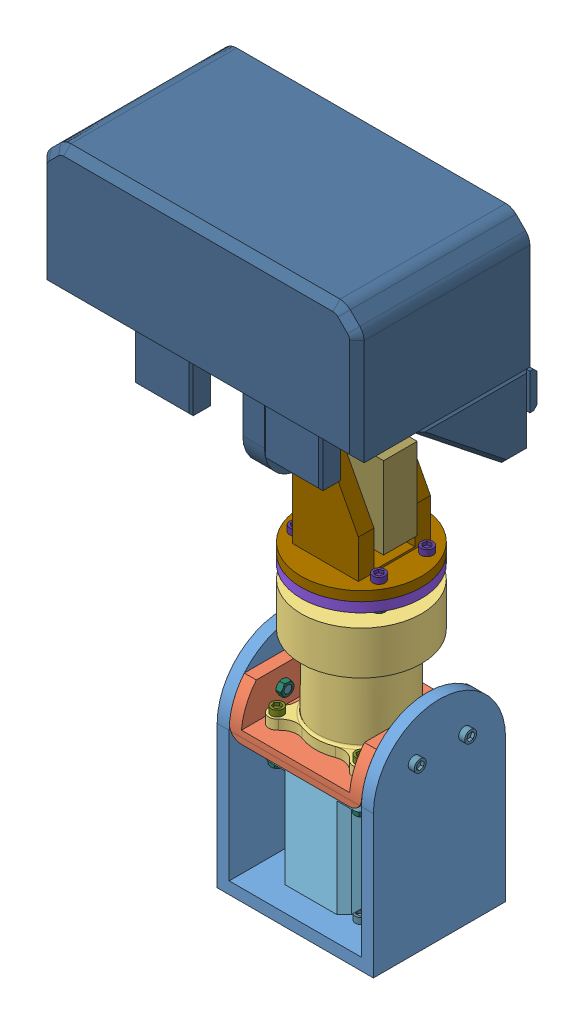
SolidWorks assembly camera, configuration Default. Lengths in mm.
Overall size (132 263.13 83.4).
66 component instances, 20 part files, 134 mates.
Components (placement in the parent):
- Part1-1: Part1 [Default] at origin size (65 86.75 55)
- Part2-1: Part2 [Default] at (0 56.75 0) x (0 0 1) z (-1 0 0) size (55 20 55)
- Part3-2: Part3 [Default] at (0 61.75 0) size (50 52 50)
- Stepper motor-1: Stepper motor [Default] at (0 56.75 0) x (0 0 1) z (-1 0 0) size (42 61 42) (flexible)
  - shaft for stpmotor-1: shaft for stpmotor [Default] at (0 -15 0) x (0.964656 0 0.263513) z (-0.263513 0 0.964656) size (5.6 28 5.6)
  - stepper motor-1-1: stepper motor-1 [Default] x (-1 0 0) z (0 0 1) size (42 48 42)
  - stepper motor-2-1: stepper motor-2 [Default] at (0 -15 0) x (0.798923 0 -0.601433) z (0.601433 0 0.798923) size (28 16.05 28)
- thrust needle bearing_is-2: thrust needle bearing_is [IS 4215 TN - AXZ614-D] at (0 102.5 0) x (0.948007 0 0.31825) z (0 -1 0) size (14 14 5.5)
- Part4-1: Part4 [Default] at (0 105.25 0) x (-1 0 0) z (0 0 -1) size (50 18 50)
- Part5-1: Part5 [Default] at (0 123.25 0) x (-1 0 0) z (0 0 -1) size (50 54 50)
- Head-1: Head [Default] at (-18.5476 153.5942 18.0553) x (-1 0 0) z (0 0 -1) size (132 111 83.4)
- Part6-1: Part6 [Default] at (-27.75 161.0422 0) x (0 -1 0) z (0 0 1) size (25 11 25)
- Servo motor-1: Servo motor [Default] at (-13.75 151.0422 0) x (0 0 1) z (0 1 0) size (14 30 44)
- servo shaft-1: servo shaft [Default] at (-19.75 161.0422 0) x (0 0.765773 -0.643111) z (0 -0.643111 -0.765773) size (5 18 5)
- M3 bolt for camera-1-1: M3 bolt for camera-1 [Default] at (-33.75 69.25 -10.5) x (0 -0.989932 0.141542) z (1 0 0) size (5 5 15.19)
- M3 bolt for camera-1-2: M3 bolt for camera-1 [Default] at (-33.75 69.25 10.5) x (0 0.287903 -0.95766) z (1 0 0) size (5 5 15.19)
- M3 bolt for camera-1-3: M3 bolt for camera-1 [Default] at (33.75 69.25 -10.5) x (0 -0.601923 0.798554) z (-1 0 0) size (5 5 15.19)
- M3 bolt for camera-1-4: M3 bolt for camera-1 [Default] at (33.75 69.25 10.5) x (0 -0.806228 0.591605) z (-1 0 0) size (5 5 15.19)
- M3 nut-1: M3 nut [Default] at (21.25 69.25 -10.5) x (0 0 -1) z (1 0 0) size (5 6.35 2.75)
- M3 nut-2: M3 nut [Default] at (21.25 69.25 10.5) x (0 0.10842 -0.994105) z (1 0 0) size (5 6.35 2.75)
- M3 nut-3: M3 nut [Default] at (-21.25 69.25 -10.5) x (0 -0.15906 -0.987269) z (1 0 0) size (5 6.35 2.75)
- M3 nut-5: M3 nut [Default] at (-21.25 69.25 10.5) x (0 -0.536596 -0.843839) z (1 0 0) size (5 6.35 2.75)
- M3 bolt for camera-1-5: M3 bolt for camera-1 [Default] at (14 6.25 -14) x (0.844498 0 0.535559) z (0 -1 0) size (5 5 15.19)
- M3 bolt for camera-1-6: M3 bolt for camera-1 [Default] at (-14 6.25 -14) x (0.844498 0 0.535559) z (0 -1 0) size (5 5 15.19)
- M3 bolt for camera-1-7: M3 bolt for camera-1 [Default] at (-14 6.25 14) x (0.844498 0 0.535559) z (0 -1 0) size (5 5 15.19)
- M3 bolt for camera-1-8: M3 bolt for camera-1 [Default] at (14 6.25 14) x (0.875078 0 0.483982) z (0 -1 0) size (5 5 15.19)
- M3 bolt for camera-2-1: M3 bolt for camera-2 [Default] at (-17.5 67 -17.5) x (0.961906 0 -0.273382) z (0 -1 0) size (5 5 21.24)
- M3 bolt for camera-2-2: M3 bolt for camera-2 [Default] at (17.5 67 -17.5) x (0.940508 0 -0.339772) z (0 -1 0) size (5 5 21.24)
- M3 bolt for camera-2-3: M3 bolt for camera-2 [Default] at (-17.5 67 17.5) x (0.940508 0 -0.339772) z (0 -1 0) size (5 5 21.24)
- M3 bolt for camera-2-4: M3 bolt for camera-2 [Default] at (17.5 67 17.5) x (0.531388 0 -0.847129) z (0 -1 0) size (5 5 21.24)
- M3 nut-6: M3 nut [Default] at (17.5 48.5 -17.5) x (0 0 -1) z (0 1 0) size (5 6.35 2.75)
- M3 nut-7: M3 nut [Default] at (17.5 48.5 17.5) x (0 0 -1) z (0 1 0) size (5 6.35 2.75)
- M3 nut-8: M3 nut [Default] at (-17.5 48.5 17.5) x (0 0 -1) z (0 -1 0) size (5 6.35 2.75)
- M3 nut-9: M3 nut [Default] at (-17.5 48.5 -17.5) x (0 0 -1) z (0 -1 0) size (5 6.35 2.75)
- M3 nut-10: M3 nut [Default] at (-14 -6.3102 14) x (-0.119007 0 -0.992893) z (0 1 0) size (5 6.35 2.75)
- M3 nut-11: M3 nut [Default] at (14 -6.2794 14) x (-0.305046 0 -0.952338) z (0 1 0) size (5 6.35 2.75)
- M3 nut-12: M3 nut [Default] at (-14 -6.1955 -14) x (-0.334167 0 -0.942514) z (0 1 0) size (5 6.35 2.75)
- M3 nut-13: M3 nut [Default] at (14 -6.5015 -14) x (0.157974 0 -0.987443) z (0 1 0) size (5 6.35 2.75)
- M3 bolt for camera-3-1: M3 bolt for camera-3 [Default] at (17.3205 128.5 10) x (0.981592 0 0.190988) z (0 -1 0) size (5 5 13.17)
- M3 bolt for camera-3-2: M3 bolt for camera-3 [Default] at (-17.3205 128.5 10) x (1 0 0) z (0 -1 0) size (5 5 13.17)
- M3 bolt for camera-3-3: M3 bolt for camera-3 [Default] at (-17.3205 128.5 -10) x (1 0 0) z (0 -1 0) size (5 5 13.17)
- M3 bolt for camera-3-4: M3 bolt for camera-3 [Default] at (17.3205 128.5 -10) x (0.282478 0 0.959274) z (0 -1 0) size (5 5 13.17)
- M3 nut-14: M3 nut [Default] at (17.3205 118 -10) x (-0.536596 0 -0.843839) z (0 -1 0) size (5 6.35 2.75)
- M3 nut-15: M3 nut [Default] at (17.3205 118 10) x (-0.536596 0 -0.843839) z (0 -1 0) size (5 6.35 2.75)
- M3 nut-16: M3 nut [Default] at (-17.3205 118 10) x (0.536596 0 -0.843839) z (0 1 0) size (5 6.35 2.75)
- M3 nut-17: M3 nut [Default] at (-17.3205 118 -10) x (0.536596 0 -0.843839) z (0 1 0) size (5 6.35 2.75)
- M3 bolt for camera-3-5: M3 bolt for camera-3 [Default] at (-8 131.0322 -4.55) x (0 0.374777 0.927115) z (-1 0 0) size (5 5 13.17)
- M3 bolt for camera-3-6: M3 bolt for camera-3 [Default] at (-8 131.0322 4.55) x (0 0.504845 0.86321) z (-1 0 0) size (5 5 13.17)
- M3 bolt for camera-3-7: M3 bolt for camera-3 [Default] at (-8 171.0522 4.55) x (0 0.374777 0.927115) z (-1 0 0) size (5 5 13.17)
- M3 bolt for camera-3-8: M3 bolt for camera-3 [Default] at (-8 171.0522 -4.55) x (0 0.374777 0.927115) z (-1 0 0) size (5 5 13.17)
- M3 nut-18: M3 nut [Default] at (-15 131.0322 4.55) x (0 -0.733053 -0.680172) z (1 0 0) size (5 6.35 2.75)
- M3 nut-19: M3 nut [Default] at (-15 131.0322 -4.55) x (0 -0.733053 -0.680172) z (1 0 0) size (5 6.35 2.75)
- M3 nut-20: M3 nut [Default] at (-15 171.0522 4.55) x (0 -0.733053 -0.680172) z (1 0 0) size (5 6.35 2.75)
- M3 nut-21: M3 nut [Default] at (-15 171.0522 -4.55) x (0 0.733053 -0.680172) z (-1 0 0) size (5 6.35 2.75)
- M3 bolt for camera-3-9: M3 bolt for camera-3 [Default] at (-32 155.0318 -6.0104) x (0 -0.010427 0.999946) z (1 0 0) size (5 5 13.17)
- M3 bolt for camera-3-11: M3 bolt for camera-3 [Default] at (-32 167.0526 6.0104) x (0 -0.369002 0.929429) z (1 0 0) size (5 5 13.17)
- M3 bolt for camera-3-12: M3 bolt for camera-3 [Default] at (-32 155.0318 6.0104) x (0 -0.369002 0.929429) z (1 0 0) size (5 5 13.17)
- M3 bolt for camera-3-13: M3 bolt for camera-3 [Default] at (-32 167.0526 -6.0104) x (0 -0.369002 0.929429) z (1 0 0) size (5 5 13.17)
- M3 nut-22: M3 nut [Default] at (-22.5 155.0318 -6.0104) x (0 0.733053 -0.680172) z (-1 0 0) size (5 6.35 2.75)
- M3 nut-23: M3 nut [Default] at (-22.5 155.0318 6.0104) x (0 -0.239551 -0.970884) z (-1 0 0) size (5 6.35 2.75)
- M3 nut-24: M3 nut [Default] at (-22.5 167.0526 6.0104) x (0 0.851142 -0.524935) z (-1 0 0) size (5 6.35 2.75)
- M3 nut-25: M3 nut [Default] at (-22.5 167.0526 -6.0104) x (0 0.997274 -0.073787) z (-1 0 0) size (5 6.35 2.75)
- M5 bolt (hl)-3: M5 bolt (hl) [Default] at (0 71.75 0) size (6.05 43.01 6.77)
- shaft coupler for camera-1: shaft coupler for camera [Default] at (0 65.75 0) x (-0.263513 0 0.964656) z (-0.964656 0 -0.263513) size (8 10.27 8)
- M5 nut-1: M5 nut [Default] at (-0.0004 77.8333 0.0043) x (0.294468 0 0.955661) z (0 -1 0) size (8.33 10.58 5.06)
- M5 nut-2: M5 nut [Default] at (-0.0004 111.3333 0.0043) x (0.294468 0 0.955661) z (0 -1 0) size (8.33 10.58 5.06)
Mates (geometry in assembly coordinates):
- Parallel2: parallel: plane of Part1-1 through (-27.5 86.75 -27.5) normal (1 0 0); plane of Stepper motor-1/stepper motor-1-1 through (-21 49.75 -17.5) normal (-1 0 0)
- Coincident4: coincident: plane of Part2-1 through (0 56.75 0) normal (0 -1 0); plane of Stepper motor-1/stepper motor-1-1 through (17.5 56.75 -17.5) normal (0 1 0)
- Coincident9: coincident: plane of Part1-1 through (0 0 0) normal (0 0 1); plane of assembly through (0 0 0) normal (0 0 1)
- Coincident10: coincident: plane of Part1-1 through (0 0 0) normal (0 1 0); plane of assembly through (0 0 0) normal (0 1 0)
- Coincident11: coincident: plane of Part1-1 through (0 0 0) normal (1 0 0); plane of assembly through (0 0 0) normal (1 0 0)
- Coincident12: coincident: plane of Part1-1 through (-27.5 86.75 -27.5) normal (1 0 0); plane of Part2-1 through (-27.5 61.75 -27.5) normal (-1 0 0)
- Coincident13: coincident: plane of Part1-1 through (-32.5 5 -27.5) normal (0 0 -1); plane of Part2-1 through (-27.5 61.75 -27.5) normal (0 0 -1)
- Concentric12: concentric: cylinder of Part1-1 through (-32.501 69.25 10.5) axis (1 0 0) radius 1.75; cylinder of Part2-1 through (-27.5 69.25 10.5) axis (1 0 0) radius 1.75
- Concentric13: concentric: cylinder of Part2-1 through (0 56.749 0) axis (0 1 0) radius 14; cylinder of Stepper motor-1/stepper motor-2-1 through (0 56.75 0) axis (0 1 0) radius 12.6
- Concentric23: concentric: cylinder of thrust needle bearing_is-2 through (0 92.3663 0) axis (0 -1 0) radius 3; cylinder of Part4-1 through (0 109.25 0) axis (0 -1 0) radius 3
- Coincident20: coincident: plane of thrust needle bearing_is-2 through (-2.0598 105.25 6.1358) normal (0 1 0); plane of Part4-1 through (0 105.25 0) normal (0 -1 0)
- Concentric26: concentric: cylinder of Part4-1 through (17.3205 105.249 10) axis (0 1 0) radius 1.75; cylinder of Part5-1 through (17.3205 127.25 10) axis (0 -1 0) radius 1.75
- Concentric27: concentric: cylinder of Part4-1 through (17.3205 105.249 -10) axis (0 1 0) radius 1.75; cylinder of Part5-1 through (17.3205 127.25 -10) axis (0 -1 0) radius 1.75
- Coincident21: coincident: plane of Part4-1 through (0 123.25 0) normal (0 1 0); plane of Part5-1 through (0 123.25 0) normal (0 -1 0)
- Coincident26: coincident: axis of Servo motor-1 through (-1.75 161.0422 0) axis (-1 0 0); axis of servo shaft-1 through (18 -1.75 161.0422) axis (0 -1 0)
- Coincident27: coincident: plane of Servo motor-1 through (-1.75 161.0422 0) normal (-1 0 0); plane of servo shaft-1 through (-1.75 161.0422 0) normal (1 0 0)
- Concentric29: concentric: circle of Part5-1; circle of Servo motor-1
- Concentric30: concentric: circle of Part5-1; circle of Servo motor-1
- Coincident28: coincident: plane of Part5-1 through (-10.75 123.25 0) normal (1 0 0); plane of Servo motor-1 through (-10.75 151.0422 0) normal (-1 0 0)
- Parallel6: parallel: plane of Servo motor-1 through (-13.75 151.0422 0) normal (-1 0 0); plane of Head-1 through (-27.75 161.0422 0) normal (1 0 0)
- Concentric31: concentric: circle of servo shaft-1; circle of Head-1
- Distance2: distance = 8 mm: plane of Head-1 through (-27.75 161.0422 0) normal (1 0 0); plane of servo shaft-1 through (-19.75 161.0422 0) normal (-1 0 0)
- Concentric38: concentric: cylinder of Part2-1 through (17.5 56.749 17.5) axis (0 1 0) radius 1.75; cylinder of Part3-2 through (17.5 65.75 17.5) axis (0 -1 0) radius 1.75
- Concentric39: concentric: cylinder of Part2-1 through (-17.5 56.749 17.5) axis (0 1 0) radius 1.75; cylinder of Part3-2 through (-17.5 65.75 17.5) axis (0 -1 0) radius 1.75
- Coincident33: coincident: plane of Part2-1 through (0 61.75 0) normal (0 1 0); plane of Part3-2 through (-4.7188 61.75 -12.1133) normal (0 -1 0)
- Concentric40: concentric: cylinder of thrust needle bearing_is-2 through (0 92.3663 0) axis (0 -1 0) radius 3; cylinder of Part3-2 through (0 99.75 0) axis (0 -1 0) radius 3
- Coincident34: coincident: plane of thrust needle bearing_is-2 through (-2.0598 99.75 6.1358) normal (0 -1 0); plane of Part3-2 through (0 99.75 0) normal (0 1 0)
- Lock1: lock: unknown of thrust needle bearing_is-2; unknown of Part4-1
- Concentric41: concentric: cylinder of Part1-1 through (32.501 69.25 -10.5) axis (-1 0 0) radius 1.75; cylinder of M3 bolt for camera-1-1 through (-32.5 69.25 -10.5) axis (-1 0 0) radius 2.5
- Concentric44: concentric: cylinder of Part1-1 through (32.501 69.25 10.5) axis (-1 0 0) radius 1.75; cylinder of M3 bolt for camera-1-2 through (-32.5 69.25 10.5) axis (-1 0 0) radius 2.5
- Concentric45: concentric: cylinder of Part1-1 through (-32.501 69.25 -10.5) axis (1 0 0) radius 1.75; cylinder of M3 bolt for camera-1-3 through (32.5 69.25 -10.5) axis (1 0 0) radius 2.5
- Concentric46: concentric: cylinder of Part1-1 through (-32.501 69.25 10.5) axis (1 0 0) radius 1.75; cylinder of M3 bolt for camera-1-4 through (32.5 69.25 10.5) axis (1 0 0) radius 2.5
- Coincident36: coincident: plane of Part1-1 through (32.5 5 27.5) normal (1 0 0); plane of M3 bolt for camera-1-4 through (32.5 69.25 10.5) normal (-1 0 0)
- Coincident37: coincident: plane of Part1-1 through (32.5 5 27.5) normal (1 0 0); plane of M3 bolt for camera-1-3 through (32.5 69.25 -10.5) normal (-1 0 0)
- Coincident38: coincident: plane of Part1-1 through (-32.5 5 27.5) normal (-1 0 0); plane of M3 bolt for camera-1-1 through (-32.5 69.25 -10.5) normal (1 0 0)
- Coincident39: coincident: plane of Part1-1 through (-32.5 5 27.5) normal (-1 0 0); plane of M3 bolt for camera-1-2 through (-32.5 69.25 10.5) normal (1 0 0)
- Coincident40: coincident: axis of M3 bolt for camera-1-3 through (20 69.25 -10.5) axis (1 0 0); axis of M3 nut-1 through (20.9044 69.25 -10.5) axis (-1 0 0)
- Coincident41: coincident: plane of Part2-1 through (22.5 76.75 -27.5) normal (-1 0 0); plane of M3 nut-1 through (22.5 69.25 -10.5) normal (1 0 0)
- Coincident42: coincident: axis of Part2-1 through (22.5 69.25 10.5) axis (1 0 0); axis of M3 nut-2 through (21.6897 69.25 10.5) axis (1 0 0)
- Coincident43: coincident: plane of Part2-1 through (22.5 76.75 -27.5) normal (-1 0 0); plane of M3 nut-2 through (22.5 69.25 10.5) normal (1 0 0)
- Coincident44: coincident: axis of Part1-1 through (-27.5 69.25 -10.5) axis (-1 0 0); axis of M3 nut-3 through (-21.5956 69.25 -10.5) axis (-1 0 0)
- Coincident45: coincident: plane of Part2-1 through (-22.5 76.75 -27.5) normal (1 0 0); plane of M3 nut-3 through (-22.5 69.25 -10.5) normal (-1 0 0)
- Coincident47: coincident: axis of M3 bolt for camera-1-2 through (-32.5 69.25 10.5) axis (-1 0 0); axis of M3 nut-5 through (-20.8103 69.25 10.5) axis (1 0 0)
- Coincident48: coincident: plane of Part2-1 through (-22.5 76.75 -27.5) normal (1 0 0); plane of M3 nut-5 through (-22.5 69.25 10.5) normal (-1 0 0)
- Concentric47: concentric: cylinder of Part1-1 through (14 86.751 -14) axis (0 -1 0) radius 1.75; cylinder of M3 bolt for camera-1-5 through (14 5 -14) axis (0 1 0) radius 2.5
- Concentric48: concentric: circle of Part1-1; cylinder of M3 bolt for camera-1-6 through (-14 5 -14) axis (0 1 0) radius 2.5
- Concentric49: concentric: cylinder of Part1-1 through (-14 86.751 14) axis (0 -1 0) radius 1.75; cylinder of M3 bolt for camera-1-7 through (-14 5 14) axis (0 1 0) radius 2.5
- Concentric50: concentric: cylinder of Part1-1 through (14 86.751 14) axis (0 -1 0) radius 1.75; cylinder of M3 bolt for camera-1-8 through (14 5 14) axis (0 1 0) radius 2.5
- Coincident49: coincident: plane of Part1-1 through (0 5 0) normal (0 1 0); plane of M3 bolt for camera-1-8 through (14 5 14) normal (0 -1 0)
- Coincident50: coincident: plane of Part1-1 through (0 5 0) normal (0 1 0); plane of M3 bolt for camera-1-7 through (-14 5 14) normal (0 -1 0)
- Coincident51: coincident: plane of Part1-1 through (0 5 0) normal (0 1 0); plane of M3 bolt for camera-1-6 through (-14 5 -14) normal (0 -1 0)
- Coincident52: coincident: plane of Part1-1 through (0 5 0) normal (0 1 0); plane of M3 bolt for camera-1-5 through (14 5 -14) normal (0 -1 0)
- Coincident55: coincident: axis of Part3-2 through (-17.5 65.75 -17.5) axis (0 -1 0); axis of M3 bolt for camera-2-1 through (-17.5 65.75 -17.5) axis (0 1 0)
- Coincident56: coincident: axis of Part3-2 through (17.5 65.75 -17.5) axis (0 -1 0); axis of M3 bolt for camera-2-2 through (17.5 47.25 -17.5) axis (0 1 0)
- Coincident57: coincident: axis of Part3-2 through (-17.5 65.75 17.5) axis (0 -1 0); axis of M3 bolt for camera-2-3 through (-17.5 47.25 17.5) axis (0 1 0)
- Coincident58: coincident: axis of Part3-2 through (17.5 65.75 17.5) axis (0 -1 0); axis of M3 bolt for camera-2-4 through (17.5 47.25 17.5) axis (0 1 0)
- Coincident59: coincident: plane of Part3-2 through (-4.7188 65.75 -12.1133) normal (0 1 0); plane of M3 bolt for camera-2-3 through (-17.5 65.75 17.5) normal (0 -1 0)
- Coincident60: coincident: plane of Part3-2 through (-4.7188 65.75 -12.1133) normal (0 1 0); plane of M3 bolt for camera-2-4 through (17.5 65.75 17.5) normal (0 -1 0)
- Coincident61: coincident: plane of Part3-2 through (-4.7188 65.75 -12.1133) normal (0 1 0); plane of M3 bolt for camera-2-2 through (17.5 65.75 -17.5) normal (0 -1 0)
- Coincident62: coincident: plane of Part3-2 through (-4.7188 65.75 -12.1133) normal (0 1 0); plane of M3 bolt for camera-2-1 through (-17.5 65.75 -17.5) normal (0 -1 0)
- Coincident65: coincident: axis of M3 bolt for camera-2-2 through (17.5 47.25 -17.5) axis (0 1 0); axis of M3 nut-6 through (17.5 48.1544 -17.5) axis (0 -1 0)
- Coincident67: coincident: axis of M3 bolt for camera-2-4 through (17.5 47.25 17.5) axis (0 1 0); axis of M3 nut-7 through (17.5 48.1544 17.5) axis (0 -1 0)
- Coincident68: coincident: axis of Stepper motor-1/stepper motor-1-1 through (-17.5 49.75 17.5) axis (0 1 0); axis of M3 nut-8 through (-17.5 48.0603 17.5) axis (0 -1 0)
- Coincident69: coincident: axis of M3 bolt for camera-2-1 through (-17.5 47.25 -17.5) axis (0 1 0); axis of M3 nut-9 through (-17.5 48.0603 -17.5) axis (0 -1 0)
- Coincident70: coincident: plane of Stepper motor-1/stepper motor-1-1 through (17.5 49.75 -17.5) normal (0 -1 0); plane of M3 nut-6 through (17.5 49.75 -17.5) normal (0 1 0)
- Coincident71: coincident: plane of Stepper motor-1/stepper motor-1-1 through (-17.5 49.75 -17.5) normal (0 -1 0); plane of M3 nut-9 through (-17.5 49.75 -17.5) normal (0 1 0)
- Coincident72: coincident: plane of Stepper motor-1/stepper motor-1-1 through (-17.5 49.75 17.5) normal (0 -1 0); plane of M3 nut-8 through (-17.5 49.75 17.5) normal (0 1 0)
- Coincident73: coincident: plane of Stepper motor-1/stepper motor-1-1 through (17.5 49.75 17.5) normal (0 -1 0); plane of M3 nut-7 through (17.5 49.75 17.5) normal (0 1 0)
- Coincident74: coincident: axis of M3 bolt for camera-1-8 through (14 -7.5 14) axis (0 1 0); axis of M3 nut-11 through (14 -5.8397 14) axis (0 1 0)
- Coincident75: coincident: axis of M3 bolt for camera-1-5 through (14 -7.5 -14) axis (0 1 0); axis of M3 nut-13 through (14 -6.0618 -14) axis (0 1 0)
- Coincident76: coincident: axis of M3 bolt for camera-1-6 through (-14 -7.5 -14) axis (0 1 0); axis of M3 nut-12 through (-14 -5.7559 -14) axis (0 1 0)
- Coincident77: coincident: axis of M3 bolt for camera-1-7 through (-14 -7.5 14) axis (0 1 0); axis of M3 nut-10 through (-14 -5.8706 14) axis (0 1 0)
- Coincident78: coincident: axis of Part5-1 through (17.3205 127.25 10) axis (0 -1 0); axis of M3 bolt for camera-3-1 through (17.3205 127.25 10) axis (0 1 0)
- Coincident79: coincident: axis of Part5-1 through (17.3205 127.25 -10) axis (0 -1 0); axis of M3 bolt for camera-3-4 through (17.3205 127.25 -10) axis (0 1 0)
- Coincident80: coincident: axis of Part5-1 through (-17.3205 127.25 -10) axis (0 -1 0); axis of M3 bolt for camera-3-3 through (-17.3205 116.75 -10) axis (0 1 0)
- Coincident81: coincident: axis of Part5-1 through (-17.3205 127.25 10) axis (0 -1 0); axis of M3 bolt for camera-3-2 through (-17.3205 116.75 10) axis (0 1 0)
- Coincident82: coincident: plane of Part5-1 through (0 127.25 0) normal (0 1 0); plane of M3 bolt for camera-3-3 through (-17.3205 127.25 -10) normal (0 -1 0)
- Coincident83: coincident: plane of Part5-1 through (0 127.25 0) normal (0 1 0); plane of M3 bolt for camera-3-2 through (-17.3205 127.25 10) normal (0 -1 0)
- Coincident84: coincident: plane of Part5-1 through (0 127.25 0) normal (0 1 0); plane of M3 bolt for camera-3-4 through (17.3205 127.25 -10) normal (0 -1 0)
- Coincident85: coincident: plane of Part5-1 through (0 127.25 0) normal (0 1 0); plane of M3 bolt for camera-3-1 through (17.3205 127.25 10) normal (0 -1 0)
- Coincident87: coincident: axis of Part4-1 through (17.3205 119.25 10) axis (0 1 0); axis of M3 nut-15 through (17.3205 117.5603 10) axis (0 -1 0)
- Coincident88: coincident: axis of Part4-1 through (17.3205 119.25 -10) axis (0 1 0); axis of M3 nut-14 through (17.3205 117.5603 -10) axis (0 -1 0)
- Coincident89: coincident: axis of Part5-1 through (-17.3205 127.25 10) axis (0 -1 0); axis of M3 nut-16 through (-17.3205 118.4397 10) axis (0 1 0)
- Coincident90: coincident: axis of Part5-1 through (-17.3205 127.25 -10) axis (0 -1 0); axis of M3 nut-17 through (-17.3205 118.4397 -10) axis (0 1 0)
- Coincident91: coincident: plane of Part4-1 through (0 119.25 0) normal (0 -1 0); plane of M3 nut-17 through (-17.3205 119.25 -10) normal (0 1 0)
- Coincident92: coincident: plane of Part4-1 through (0 119.25 0) normal (0 -1 0); plane of M3 nut-16 through (-17.3205 119.25 10) normal (0 1 0)
- Coincident93: coincident: plane of Part4-1 through (0 119.25 0) normal (0 -1 0); plane of M3 nut-14 through (17.3205 119.25 -10) normal (0 1 0)
- Coincident94: coincident: plane of Part4-1 through (0 119.25 0) normal (0 -1 0); plane of M3 nut-15 through (17.3205 119.25 10) normal (0 1 0)
- Coincident95: coincident: axis of Part5-1 through (-13.75 131.0322 -4.55) axis (1 0 0); axis of M3 bolt for camera-3-5 through (-9.25 131.0322 -4.55) axis (1 0 0)
- Coincident96: coincident: axis of Part5-1 through (-13.75 131.0322 4.55) axis (1 0 0); axis of M3 bolt for camera-3-6 through (-19.75 131.0322 4.55) axis (1 0 0)
- Coincident97: coincident: axis of Part5-1 through (-13.75 171.0522 4.55) axis (1 0 0); axis of M3 bolt for camera-3-7 through (-19.75 171.0522 4.55) axis (1 0 0)
- Coincident98: coincident: axis of Servo motor-1 through (-9.25 171.0522 -4.55) axis (-1 0 0); axis of M3 bolt for camera-3-8 through (-9.25 171.0522 -4.55) axis (1 0 0)
- Coincident99: coincident: plane of Servo motor-1 through (-9.25 151.0422 0) normal (1 0 0); plane of M3 bolt for camera-3-8 through (-9.25 171.0522 -4.55) normal (-1 0 0)
- Coincident100: coincident: plane of Servo motor-1 through (-9.25 151.0422 0) normal (1 0 0); plane of M3 bolt for camera-3-7 through (-9.25 171.0522 4.55) normal (-1 0 0)
- Coincident101: coincident: plane of Servo motor-1 through (-9.25 151.0422 0) normal (1 0 0); plane of M3 bolt for camera-3-5 through (-9.25 131.0322 -4.55) normal (-1 0 0)
- Coincident102: coincident: plane of Servo motor-1 through (-9.25 151.0422 0) normal (1 0 0); plane of M3 bolt for camera-3-6 through (-9.25 131.0322 4.55) normal (-1 0 0)
- Coincident103: coincident: axis of M3 bolt for camera-3-6 through (-19.75 131.0322 4.55) axis (1 0 0); axis of M3 nut-18 through (-13.75 131.0322 4.55) axis (-1 0 0)
- Coincident104: coincident: axis of M3 bolt for camera-3-5 through (-19.75 131.0322 -4.55) axis (1 0 0); axis of M3 nut-19 through (-13.75 131.0322 -4.55) axis (-1 0 0)
- Coincident105: coincident: axis of M3 bolt for camera-3-7 through (-19.75 171.0522 4.55) axis (1 0 0); axis of M3 nut-20 through (-15.3456 171.0522 4.55) axis (-1 0 0)
- Coincident106: coincident: axis of M3 bolt for camera-3-8 through (-19.75 171.0522 -4.55) axis (1 0 0); axis of M3 nut-21 through (-15.4397 171.0522 -4.55) axis (-1 0 0)
- Coincident107: coincident: plane of Part5-1 through (-13.75 177.25 -15) normal (-1 0 0); plane of M3 nut-21 through (-13.75 171.0522 -4.55) normal (1 0 0)
- Coincident108: coincident: plane of Part5-1 through (-13.75 177.25 -15) normal (-1 0 0); plane of M3 nut-20 through (-13.75 171.0522 4.55) normal (1 0 0)
- Coincident110: coincident: plane of Part5-1 through (-13.75 177.25 -15) normal (-1 0 0); plane of M3 nut-19 through (-13.75 131.0322 -4.55) normal (1 0 0)
- Coincident111: coincident: plane of Part5-1 through (-13.75 177.25 -15) normal (-1 0 0); plane of M3 nut-18 through (-13.75 131.0322 4.55) normal (1 0 0)
- Coincident112: coincident: plane of servo shaft-1 through (-19.75 161.0422 0) normal (-1 0 0); plane of Part6-1 through (-19.75 161.0422 0) normal (1 0 0)
- Concentric52: concentric: cylinder of servo shaft-1 through (-1.75 161.0422 0) axis (-1 0 0) radius 2.5; cylinder of Part6-1 through (-16.75 161.0422 0) axis (-1 0 0) radius 2.5
- Concentric53: concentric: cylinder of Head-1 through (-85.8324 167.0526 -6.0104) axis (1 0 0) radius 1.75; cylinder of Part6-1 through (-27.751 167.0526 -6.0104) axis (1 0 0) radius 1.75
- Coincident129: coincident: axis of Part6-1 through (-27.75 155.0318 -6.0104) axis (1 0 0); axis of M3 bolt for camera-3-9 through (-20.25 155.0318 -6.0104) axis (-1 0 0)
- Coincident130: coincident: axis of Head-1 through (-30.75 167.0526 -6.0104) axis (1 0 0); axis of M3 bolt for camera-3-13 through (-20.25 167.0526 -6.0104) axis (-1 0 0)
- Coincident131: coincident: axis of Part6-1 through (-27.75 155.0318 6.0104) axis (1 0 0); axis of M3 bolt for camera-3-12 through (-20.25 155.0318 6.0104) axis (-1 0 0)
- Coincident132: coincident: axis of Part6-1 through (-27.75 167.0526 6.0104) axis (1 0 0); axis of M3 bolt for camera-3-11 through (-20.25 167.0526 6.0104) axis (-1 0 0)
- Coincident133: coincident: plane of Head-1 through (-30.75 144.2561 -18.5866) normal (-1 0 0); plane of M3 bolt for camera-3-13 through (-30.75 167.0526 -6.0104) normal (1 0 0)
- Coincident134: coincident: plane of Head-1 through (-30.75 144.2561 -18.5866) normal (-1 0 0); plane of M3 bolt for camera-3-11 through (-30.75 167.0526 6.0104) normal (1 0 0)
- Coincident135: coincident: plane of Head-1 through (-30.75 144.2561 -18.5866) normal (-1 0 0); plane of M3 bolt for camera-3-12 through (-30.75 155.0318 6.0104) normal (1 0 0)
- Coincident136: coincident: plane of Head-1 through (-30.75 144.2561 -18.5866) normal (-1 0 0); plane of M3 bolt for camera-3-9 through (-30.75 155.0318 -6.0104) normal (1 0 0)
- Coincident137: coincident: axis of M3 bolt for camera-3-11 through (-30.75 167.0526 6.0104) axis (-1 0 0); axis of M3 nut-24 through (-23.75 167.0526 6.0104) axis (1 0 0)
- Coincident138: coincident: axis of M3 bolt for camera-3-13 through (-30.75 167.0526 -6.0104) axis (-1 0 0); axis of M3 nut-25 through (-22.9397 167.0526 -6.0104) axis (-1 0 0)
- Coincident139: coincident: axis of M3 bolt for camera-3-9 through (-30.75 155.0318 -6.0104) axis (-1 0 0); axis of M3 nut-22 through (-22.9397 155.0318 -6.0104) axis (-1 0 0)
- Coincident140: coincident: axis of M3 bolt for camera-3-12 through (-30.75 155.0318 6.0104) axis (-1 0 0); axis of M3 nut-23 through (-22.9397 155.0318 6.0104) axis (-1 0 0)
- Coincident141: coincident: plane of Part6-1 through (-23.75 161.0422 0) normal (1 0 0); plane of M3 nut-23 through (-23.75 155.0318 6.0104) normal (-1 0 0)
- Coincident142: coincident: plane of Part6-1 through (-23.75 161.0422 0) normal (1 0 0); plane of M3 nut-22 through (-23.75 155.0318 -6.0104) normal (-1 0 0)
- Coincident143: coincident: plane of Part6-1 through (-23.75 161.0422 0) normal (1 0 0); plane of M3 nut-24 through (-23.75 167.0526 6.0104) normal (-1 0 0)
- Coincident144: coincident: plane of Part6-1 through (-23.75 161.0422 0) normal (1 0 0); plane of M3 nut-25 through (-23.75 167.0526 -6.0104) normal (-1 0 0)
- LimitAngle1: limit planar angle = 0 rad: plane of Part5-1 through (-13.75 177.25 -15) normal (0 0 -1); plane of Head-1 through (22.1686 198.2561 -18.5866) normal (0 0 -1)
- Coincident145: coincident: axis of M5 bolt (hl)-3 through (42 0 113.75) axis (0 0 -1); axis of shaft coupler for camera-1 through (3.4 0 72.35) axis (0 0 1)
- Coincident146: coincident: plane of M5 bolt (hl)-3 through (0 71.75 0) normal (0 -1 0); plane of shaft coupler for camera-1 through (0 71.75 0) normal (0 1 0)
- Coincident147: coincident: plane of Stepper motor-1/shaft for stpmotor-1 through (-0.2635 59.75 0.9647) normal (-0.263513 0 0.964656); plane of shaft coupler for camera-1 through (-2.4738 69.75 0.3609) normal (0.263513 0 -0.964656)
- Coincident148: coincident: axis of Stepper motor-1/shaft for stpmotor-1 through (28 0 69.75) axis (0 0 -1); axis of shaft coupler for camera-1 through (10 0 75.75) axis (0 0 -1)
- Coincident149: coincident: plane of Stepper motor-1/shaft for stpmotor-1 through (0 69.75 0) normal (0 1 0); plane of shaft coupler for camera-1 through (0 69.75 0) normal (0 -1 0)
- Coincident150: coincident: axis of M5 bolt (hl)-3 through (42 0 113.75) axis (0 0 -1); axis of M5 nut-1 through (2.8348 0 78.4093) axis (0 0 1)
- Coincident151: coincident: plane of shaft coupler for camera-1 through (0 75.75 0) normal (0 1 0); plane of M5 nut-1 through (0 75.75 0) normal (0 -1 0)
- Coincident152: coincident: axis of Part4-1 through (0 119.25 0) axis (0 -1 0); axis of M5 nut-2 through (2.8348 0 111.9093) axis (0 0 1)
- Coincident153: coincident: plane of Part4-1 through (0 109.25 0) normal (0 1 0); plane of M5 nut-2 through (0 109.25 0) normal (0 -1 0)
- LimitAngle2: limit planar angle = 0 rad: plane of Part5-1 through (-13.75 177.25 -15) normal (0 0 -1); plane of Part1-1 through (-32.5 5 -27.5) normal (0 0 -1)
